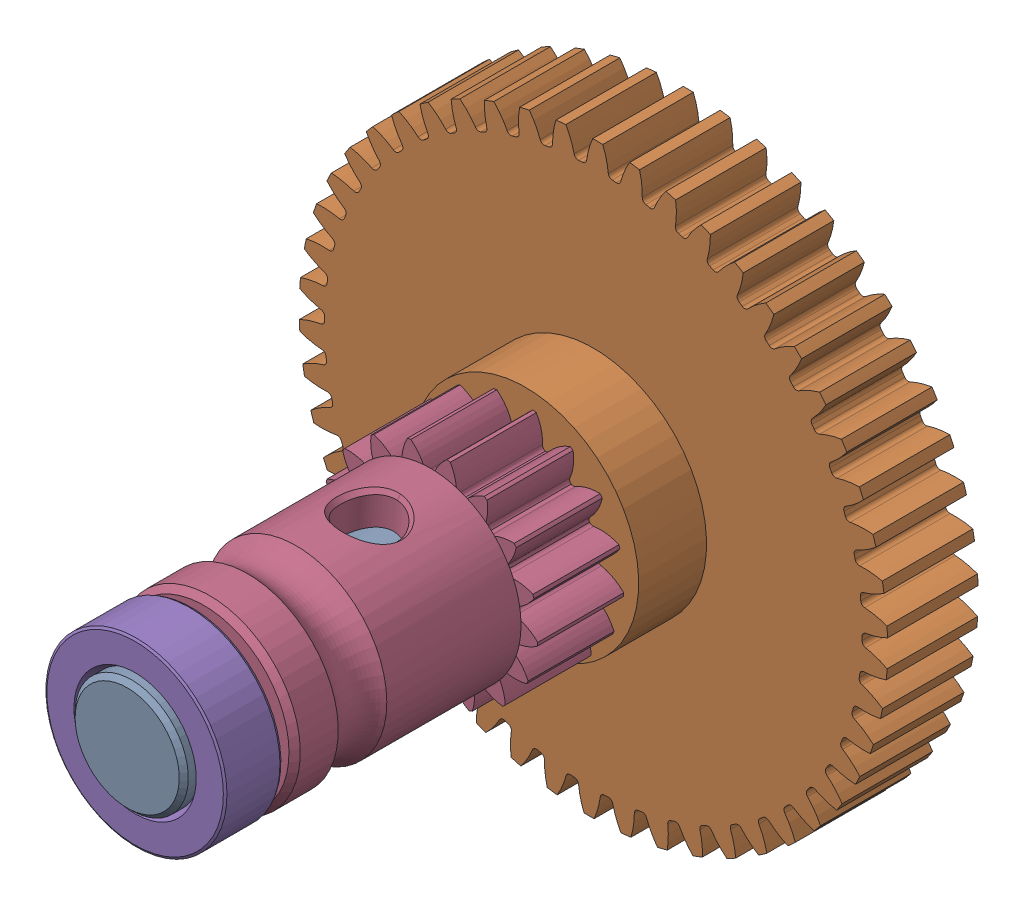
SolidWorks assembly Driveshaft Assembly, configuration Default. Lengths in mm.
Overall size (27.94 27.91 28).
6 component instances, 4 part files, 0 mates.
Components (placement in the parent):
- Shaft-assembly-1: Shaft-assembly [Default] at (24.3081 94.4506 -53.9704) x (0 0 -1) z (0.077566 0.996987 0) size (28 26 25.97)
  - Shaft-assembly-1: Shaft-assembly [Default] at origin size (28 5 5)
  - Shaft-assembly_2-1: Shaft-assembly_2 [Default] at origin size (7.5 26 25.97)
- MR825 Ballbearing 5x8x2-1: MR825 Ballbearing 5x8x2 [Default] at (20.7338 94.7286 -54.972) x (0.2227 -0.974887 0) z (0 0 1) size (8 8 2.5)
- Direct_Drivegear-1: Direct_Drivegear [Default] at (20.7338 94.7286 -42.6707) x (-0.077566 -0.996987 0) z (0 0 1) size (9.47 9.43 13.8)
- MR825 Ballbearing 5x8x2-2: MR825 Ballbearing 5x8x2 [Default] at (20.7338 94.7286 -29.8717) x (0.132022 -0.991247 0) z (0 0 1) size (8 8 2.5)
